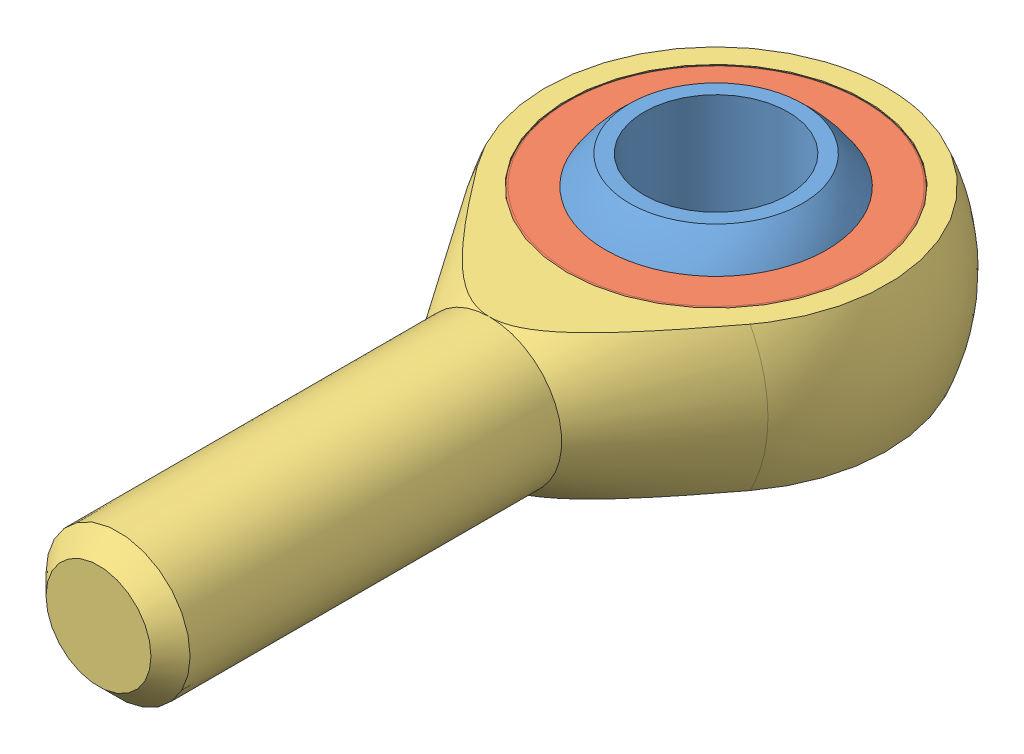
SolidWorks assembly Przegub kulowy_GN 648.2_14, configuration Domyślna. Lengths in mm.
Overall size (36 19 78).
3 component instances, 3 part files, 8 mates.
Components (placement in the parent):
- ROD-END-GN-648.2-1-14-1: ROD-END-GN-648.2-1-14 [14] x (-1 0 0) z (0 0 -1) size (25.36 19 25.36)
- ROD-END-GN-648.2-2-14-1: ROD-END-GN-648.2-2-14 [14] x (0.997964 0 0.063787) z (-0.063787 0 0.997964) size (29 13.5 29)
- ROD-END-GN-648.2-3-14-1: ROD-END-GN-648.2-3-14 [14] at (0 -0.25 0) size (36 14 78)
Mates (geometry in assembly coordinates):
- Koncentryczne1: concentric: sphere of ROD-END-GN-648.2-2-14-1; sphere of ROD-END-GN-648.2-1-14-1
- Limit kąta1: limit planar angle = 0 rad aligned: cylinder of ROD-END-GN-648.2-1-14-1 through (0 -11.1 0) axis (0 -1 0) radius 7
- Limit kąta2: limit planar angle = 0 rad aligned: cylinder of ROD-END-GN-648.2-2-14-1 through (0 6.75 0) axis (0 -1 0) radius 14.5
- Koncentryczne5: concentric anti-aligned: cylinder of ROD-END-GN-648.2-3-14-1 through (0 -7.25 0) axis (0 1 0) radius 14.5; cylinder of ROD-END-GN-648.2-2-14-1 through (0 6.75 0) axis (0 -1 0) radius 14.5
- Wspólnie1: coincident aligned: plane of ROD-END-GN-648.2-3-14-1 through (-18 6.75 22) normal (0 1 0); plane of ROD-END-GN-648.2-2-14-1 through (0 6.75 0) normal (0 1 0)
- Wspólnie2: coincident anti-aligned: plane of ROD-END-GN-648.2-1-14-1 through (0 0 0) normal (0 0 -1)
- Wspólnie3: coincident aligned: plane of ROD-END-GN-648.2-1-14-1 through (0 0 0) normal (0 1 0)
- Wspólnie4: coincident anti-aligned: plane of ROD-END-GN-648.2-1-14-1 through (0 0 0) normal (-1 0 0)
